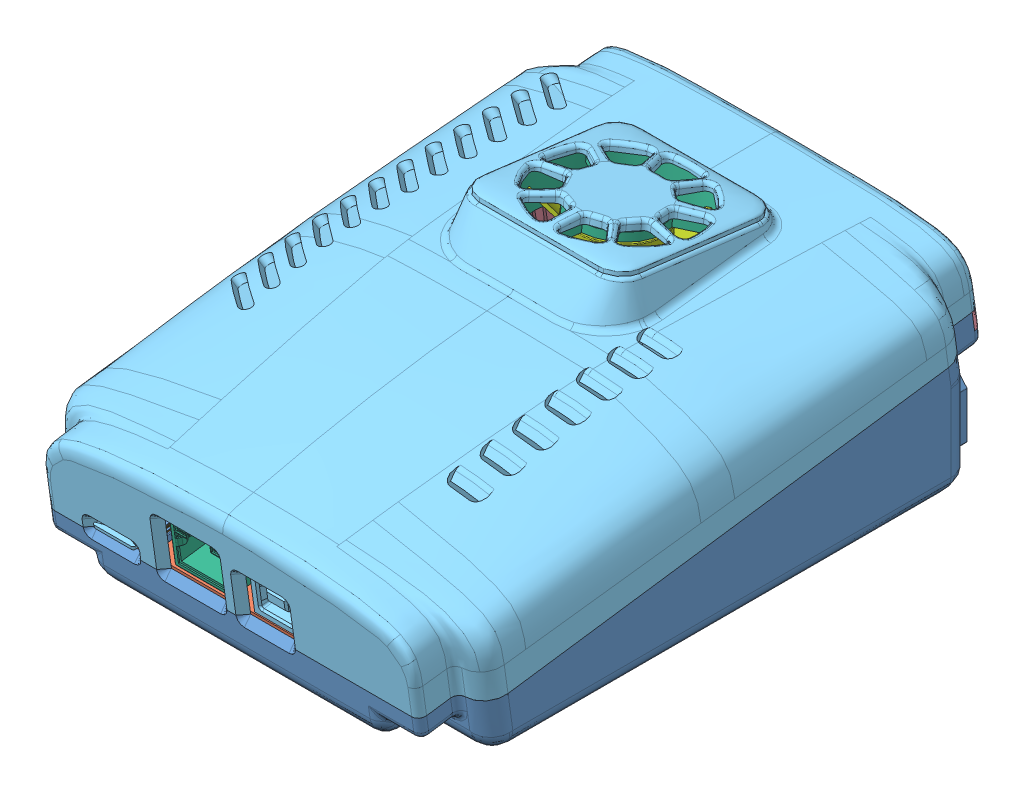
SolidWorks assembly MKS Sbase case new, configuration Default. Lengths in mm.
Overall size (115.99 69.47 159.81).
163 component instances, 61 part files, 40 mates.
Components (placement in the parent):
- MKS SBase case bottom V1.3-1: MKS SBase case bottom V1.3 [Default] at origin size (115.99 31.84 151.44)
- MKS SBase V1.3-1: MKS SBase V1.3 [Default] at (0 1.2873 0.1809) x (0 0.139173 -0.990268) z (1 0 0) size (148.75 28.07 98.65)
  - MKS SBase PCB-1: MKS SBase PCB [Default] at origin size (146.5 1.6 95)
  - 10 pin male socket -2: 10 pin male socket  [Default] at (92.5901 0 -6.7406) x (0 0 -1) z (1 0 0) size (20.25 12.5 9)
  - 10 pin male socket -3: 10 pin male socket  [Default] at (92.5901 0 -28.4906) x (0 0 -1) z (1 0 0) size (20.25 12.5 9)
  - 6 pin terminal block-1: 6 pin terminal block [Default] at (-13.25 0 37.7021) size (30.6 13.8 8.3)
  - USB socket-1: USB socket [Default] at (-15.2875 4.6912 16.0684) size (16.5 14.22 14.86)
  - JST XH 4 Purple-1: JST XH 4 Purple [Default] at (56.25 0 -43.725) x (-1 0 0) z (0 0 -1) size (12.4 10.45 5.75)
  - JST XH 4 Black-1: JST XH 4 Black [Default] at (36.35 0 -43.725) x (-1 0 0) z (0 0 -1) size (12.4 10.45 5.75)
  - JST XH 4 Blue-1: JST XH 4 Blue [Default] at (-3.45 0 -43.725) x (-1 0 0) z (0 0 -1) size (12.4 10.45 5.75)
  - JST XH 4 Green-1: JST XH 4 Green [Default] at (16.45 0 -43.725) x (-1 0 0) z (0 0 -1) size (12.4 10.45 5.75)
  - JST XH 4 Red-1: JST XH 4 Red [Default] at (-23.35 0 -43.725) x (-1 0 0) z (0 0 -1) size (12.4 10.45 5.75)
  - JST XH 2 Black-1: JST XH 2 Black [Default] at (13.85 0 44.225) size (7.4 10.45 5.75)
  - JST XH 2 Purple-1: JST XH 2 Purple [Default] at (21.75 0 44.225) size (7.4 10.45 5.75)
  - JST XH 2 White-1: JST XH 2 White [Default] at (5.95 0 44.225) size (7.4 10.45 5.75)
  - JST XH 3 Blue-1: JST XH 3 Blue [Default] at (55.4 0 14.725) x (-1 0 0) z (0 0 -1) size (9.9 10.45 5.75)
  - JST XH 3 Green-1: JST XH 3 Green [Default] at (55.4 0 31.025) x (-1 0 0) z (0 0 -1) size (9.9 10.45 5.75)
  - JST XH 3 Red-1: JST XH 3 Red [Default] at (55.4 0 -1.575) x (-1 0 0) z (0 0 -1) size (9.9 10.45 5.75)
  - JST XH 2 White-2: JST XH 2 White [Default] at (29.65 0 44.225) size (7.4 10.45 5.75)
  - 8 pin male socket -1: 8 pin male socket  [Default] at (71.2406 0 66.9901) size (17.85 12.5 9)
  - JST XH 3 Blue-2: JST XH 3 Blue [Default] at (55.4 0 6.675) x (-1 0 0) z (0 0 -1) size (9.9 10.45 5.75)
  - JST XH 3 Green-2: JST XH 3 Green [Default] at (55.4 0 22.975) x (-1 0 0) z (0 0 -1) size (9.9 10.45 5.75)
  - JST XH 3 Red-2: JST XH 3 Red [Default] at (55.4 0 -9.625) x (-1 0 0) z (0 0 -1) size (9.9 10.45 5.75)
  - microSD_Connector-1: microSD_Connector [Default] at (-65.65 0 -31.475) x (0 0 -1) z (1 0 0) size (14.1 2.14 15.45)
    - microSD_Body-1: microSD_Body [Default] at origin size (14.1 1.85 15.2)
    - microSD_Cover-1: microSD_Cover [Default] at (0 1.7 0) x (1 0 0) z (0 0 -1) size (13.95 1.9 15.2)
    - microSD_Card_Detect-1: microSD_Card_Detect [Default] at (4.99 -0.05 7.4) size (4.45 1.9 2.05)
    - microSD_Spring-2: microSD_Spring [Default] at (-3.85 1.125 6.9) x (-0.521999 -0.852946 0) z (0.852946 -0.521999 0) size (1.41 10.35 1.43)
    - microSD_Pin-1: microSD_Pin [11.15] at (5.725 -0.05 -2) x (0 0 1) z (-1 0 0) size (7.35 1.15 0.6)
    - microSD_Pin-2: microSD_Pin [11.15] at (4.625 -0.05 -2) x (0 0 1) z (-1 0 0) size (7.35 1.15 0.6)
    - microSD_Pin-3: microSD_Pin [11.35] at (3.525 -0.05 -2) x (0 0 1) z (-1 0 0) size (7.35 1.15 0.6)
    - microSD_Pin-4: microSD_Pin [11.15] at (2.425 -0.05 -2) x (0 0 1) z (-1 0 0) size (7.35 1.15 0.6)
    - microSD_Pin-5: microSD_Pin [11.35] at (1.325 -0.05 -2) x (0 0 1) z (-1 0 0) size (7.35 1.15 0.6)
    - microSD_Pin-6: microSD_Pin [11.15] at (0.225 -0.05 -2) x (0 0 1) z (-1 0 0) size (7.35 1.15 0.6)
    - microSD_Pin-7: microSD_Pin [10.75] at (-0.875 -0.05 -2) x (0 0 1) z (-1 0 0) size (7.25 1.15 0.6)
    - microSD_Pin-8: microSD_Pin [11.15] at (-1.975 -0.05 -2) x (0 0 1) z (-1 0 0) size (7.35 1.15 0.6)
  - Micro SD Card-1: Micro SD Card [Default] at (-68 1.05 -33.35) x (0 0 1) z (-1 0 0) size (11 0.83 15)
  - RJ45_10P_TJ3009-1: RJ45_10P_TJ3009 [Default] at (-61.925 0.35 -11.1) x (0 0 1) z (-1 0 0) size (16 15.87 21.5)
  - Condensator-1: Condensator [Default] at (-65.75 0.15 24) x (-1 0 0) z (0 0 -1) size (13.15 23 13.15)
  - Condensator-2: Condensator [Default] at (-50.75 0.15 24) x (-1 0 0) z (0 0 -1) size (13.15 23 13.15)
  - 2.54 pins 4 x 1-1: 2.54 pins 4 x 1 [Default] at (-14.68 0 -18.75) x (1 0 0) z (0 0 -1) size (10.06 11 2.5)
  - 2.54 pins 4 x 1-5: 2.54 pins 4 x 1 [Default] at (25.12 0 -18.75) x (1 0 0) z (0 0 -1) size (10.06 11 2.5)
  - 2.54 pins 4 x 1-6: 2.54 pins 4 x 1 [Default] at (45.02 0 -18.75) x (1 0 0) z (0 0 -1) size (10.06 11 2.5)
  - 2.54 pins 4 x 1-7: 2.54 pins 4 x 1 [Default] at (64.92 0 -18.75) x (1 0 0) z (0 0 -1) size (10.06 11 2.5)
  - 2.54 pins 4 x 1-8: 2.54 pins 4 x 1 [Default] at (5.22 0 -18.75) x (1 0 0) z (0 0 -1) size (10.06 11 2.5)
  - 2.54 pins 6 x 1-1: 2.54 pins 6 x 1 [Default] at (71 0 -37.8175) x (0 0 1) z (-1 0 0) size (15.09 11 2.5)
  - 2.54 pins 6 x 1-3: 2.54 pins 6 x 1 [Default] at (-51.2675 0 -45.4) size (15.09 11 2.5)
  - 2.54 pins 3 x 1-3: 2.54 pins 3 x 1 [Default] at (55.6125 0 36.35) size (7.47 11 2.5)
  - 2.54 pins 3 x 1-4: 2.54 pins 3 x 1 [Default] at (64.6 0 -30.2125) x (0 0 -1) z (1 0 0) size (7.47 11 2.5)
  - 2.54 pins 2 x 1-1: 2.54 pins 2 x 1 [Default] at (4.5 0 19.2475) x (0 0 -1) z (1 0 0) size (4.93 11 2.5)
  - 2.54 pins 3 x 2-3: 2.54 pins 3 x 2 [Default] at (-42.5 0.64 7.0875) x (0 0 -1) z (1 0 0) size (7.47 8.64 7.5)
  - Stepper driver heatsink-1: Stepper driver heatsink [Default] at (15.75 9.25 -28.85) x (0 0 -1) z (1 0 0) size (6 13.5 90)
  - Stepper driver-1: Stepper driver [Default] at (55.75 1.35 -28.85) x (0 0 -1) z (1 0 0) size (8 2.5 10.5)
  - Stepper driver-2: Stepper driver [Default] at (35.75 1.35 -28.85) x (0 0 -1) z (1 0 0) size (8 2.5 10.5)
  - Stepper driver-3: Stepper driver [Default] at (15.75 1.35 -28.85) x (0 0 -1) z (1 0 0) size (8 2.5 10.5)
  - Stepper driver-4: Stepper driver [Default] at (-4.25 1.35 -28.85) x (0 0 -1) z (1 0 0) size (8 2.5 10.5)
  - Stepper driver-5: Stepper driver [Default] at (-24.25 1.35 -28.85) x (0 0 -1) z (1 0 0) size (8 2.5 10.5)
  - Power terminal block-1: Power terminal block [Default] at (-51.75 0 42.25) x (-1 0 0) z (0 0 -1) size (10.55 20.8 10.5)
  - Power terminal block-2: Power terminal block [Default] at (-34.75 0 42.25) x (-1 0 0) z (0 0 -1) size (10.55 20.8 10.5)
  - Elco100_35-5: Elco100_35 [Default] at (-30.25 0.64 -4.7) x (0 0 1) z (-1 0 0) size (6.6 6.95 7)
  - Elco100_35-6: Elco100_35 [Default] at (24.65 0.64 11.3) x (0 0 -1) z (1 0 0) size (6.6 6.95 7)
  - Elco100_35-7: Elco100_35 [Default] at (-32.05 0.64 -36) x (0 0 -1) z (1 0 0) size (6.6 6.95 7)
  - Elco100_35-8: Elco100_35 [Default] at (-12.05 0.64 -36) x (0 0 -1) z (1 0 0) size (6.6 6.95 7)
  - Elco100_35-9: Elco100_35 [Default] at (7.95 0.64 -36) x (0 0 -1) z (1 0 0) size (6.6 6.95 7)
  - Elco100_35-10: Elco100_35 [Default] at (27.95 0.64 -36) x (0 0 -1) z (1 0 0) size (6.6 6.95 7)
  - Elco100_35-11: Elco100_35 [Default] at (47.95 0.64 -36) x (0 0 -1) z (1 0 0) size (6.6 6.95 7)
  - Elco10_35-1: Elco10_35 [Default] at (35.2 0.64 35.25) size (4.3 4.65 4.6)
  - Elco10_35-2: Elco10_35 [Default] at (28.35 0.64 35.25) size (4.3 4.65 4.6)
  - Elco10_35-3: Elco10_35 [Default] at (21.5 0.64 35.25) size (4.3 4.65 4.6)
  - Elco10_35-4: Elco10_35 [Default] at (14.65 0.64 35.25) size (4.3 4.65 4.6)
  - Power FAT heatsink-1: Power FAT heatsink [Default] at (-16.55 2 30.7) size (55 11.25 8.49)
  - Power FAT-1: Power FAT [Default] at (-34.925 0 30.7) x (-1 0 0) z (0 0 -1) size (6.35 2 11)
  - Power FAT-2: Power FAT [Default] at (-22.675 0 30.7) x (-1 0 0) z (0 0 -1) size (6.35 2 11)
  - Power FAT-3: Power FAT [Default] at (-10.425 0 30.7) x (-1 0 0) z (0 0 -1) size (6.35 2 11)
  - Power FAT-4: Power FAT [Default] at (1.825 0 30.7) x (-1 0 0) z (0 0 -1) size (6.35 2 11)
  - Series of LEDs-1: Series of LEDs [Default] at (-46.425 0 -41.575) size (10.85 0.6 1.75)
  - Reset button-1: Reset button [Default] at (59.9 0 43.2) size (9.25 2.95 6.02)
  - 4 LEDs power outputs-1: 4 LEDs power outputs [Default] at (-12.2 0 25.075) size (37.6 0.6 1.75)
  - LPC1768 ARM Cortex M3-1: LPC1768 ARM Cortex M3 [Default] at (-15.75 0 2.3) size (17 1.4 17)
  - Elco10_35-6: Elco10_35 [Default] at (-29.9 0.64 -10.6) x (0 0 1) z (-1 0 0) size (4.3 4.65 4.6)
  - Elco10_35-7: Elco10_35 [Default] at (2.4 0.64 -9.1) size (4.3 4.65 4.6)
  - Elco10_35-8: Elco10_35 [Default] at (15.6 0.64 3.35) size (4.3 4.65 4.6)
  - Elco10_35-9: Elco10_35 [Default] at (-37.9 0.64 -20.4) size (4.3 4.65 4.6)
  - JST Stepper connector assembly-1: JST Stepper connector assembly [Default] at (36.35 1.2 -43.75) size (12.3 15.75 8.2)
    - JST XHP 4-1: JST XHP 4 [Default] at origin size (12.3 8 5.45)
    - JSH XHP Contact Pin-1: JSH XHP Contact Pin [Default] at (-3.75 1 0.25) size (2 6.61 2.5)
    - JSH XHP Contact Pin-2: JSH XHP Contact Pin [Default] at (3.75 1 0.25) size (2 6.61 2.5)
    - JSH XHP Contact Pin-3: JSH XHP Contact Pin [Default] at (1.25 1 0.25) size (2 6.61 2.5)
    - JSH XHP Contact Pin-4: JSH XHP Contact Pin [Default] at (-1.25 1 0.25) size (2 6.61 2.5)
    - Stepper wire Black-1: Stepper wire Black [Default] at (3.75 0 -0.0046) size (1.4 15.75 6.79)
    - Stepper wire Green-1: Stepper wire Green [Default] at (1.25 0 -0.0046) size (1.4 15.75 6.79)
    - Stepper wire Red-1: Stepper wire Red [Default] at (-1.25 0 -0.0046) size (1.4 15.75 6.79)
    - Stepper wire Blue-1: Stepper wire Blue [Default] at (-3.75 0 -0.0046) size (1.4 15.75 6.79)
  - JST Stepper connector assembly-2: JST Stepper connector assembly [Default] at (16.45 1.2 -43.75) size (12.3 15.75 8.2)
    - JST XHP 4-1: JST XHP 4 [Default] at origin size (12.3 8 5.45)
    - JSH XHP Contact Pin-1: JSH XHP Contact Pin [Default] at (-3.75 1 0.25) size (2 6.61 2.5)
    - JSH XHP Contact Pin-2: JSH XHP Contact Pin [Default] at (3.75 1 0.25) size (2 6.61 2.5)
    - JSH XHP Contact Pin-3: JSH XHP Contact Pin [Default] at (1.25 1 0.25) size (2 6.61 2.5)
    - JSH XHP Contact Pin-4: JSH XHP Contact Pin [Default] at (-1.25 1 0.25) size (2 6.61 2.5)
    - Stepper wire Black-1: Stepper wire Black [Default] at (3.75 0 -0.0046) size (1.4 15.75 6.79)
    - Stepper wire Green-1: Stepper wire Green [Default] at (1.25 0 -0.0046) size (1.4 15.75 6.79)
    - Stepper wire Red-1: Stepper wire Red [Default] at (-1.25 0 -0.0046) size (1.4 15.75 6.79)
    - Stepper wire Blue-1: Stepper wire Blue [Default] at (-3.75 0 -0.0046) size (1.4 15.75 6.79)
  - JST Stepper connector assembly-3: JST Stepper connector assembly [Default] at (-3.45 1.2 -43.75) size (12.3 15.75 8.2)
    - JST XHP 4-1: JST XHP 4 [Default] at origin size (12.3 8 5.45)
    - JSH XHP Contact Pin-1: JSH XHP Contact Pin [Default] at (-3.75 1 0.25) size (2 6.61 2.5)
    - JSH XHP Contact Pin-2: JSH XHP Contact Pin [Default] at (3.75 1 0.25) size (2 6.61 2.5)
    - JSH XHP Contact Pin-3: JSH XHP Contact Pin [Default] at (1.25 1 0.25) size (2 6.61 2.5)
    - JSH XHP Contact Pin-4: JSH XHP Contact Pin [Default] at (-1.25 1 0.25) size (2 6.61 2.5)
    - Stepper wire Black-1: Stepper wire Black [Default] at (3.75 0 -0.0046) size (1.4 15.75 6.79)
    - Stepper wire Green-1: Stepper wire Green [Default] at (1.25 0 -0.0046) size (1.4 15.75 6.79)
    - Stepper wire Red-1: Stepper wire Red [Default] at (-1.25 0 -0.0046) size (1.4 15.75 6.79)
    - Stepper wire Blue-1: Stepper wire Blue [Default] at (-3.75 0 -0.0046) size (1.4 15.75 6.79)
  - JST Stepper connector assembly-4: JST Stepper connector assembly [Default] at (-23.35 1.2 -43.75) size (12.3 15.75 8.2)
    - JST XHP 4-1: JST XHP 4 [Default] at origin size (12.3 8 5.45)
    - JSH XHP Contact Pin-1: JSH XHP Contact Pin [Default] at (-3.75 1 0.25) size (2 6.61 2.5)
    - JSH XHP Contact Pin-2: JSH XHP Contact Pin [Default] at (3.75 1 0.25) size (2 6.61 2.5)
    - JSH XHP Contact Pin-3: JSH XHP Contact Pin [Default] at (1.25 1 0.25) size (2 6.61 2.5)
    - JSH XHP Contact Pin-4: JSH XHP Contact Pin [Default] at (-1.25 1 0.25) size (2 6.61 2.5)
    - Stepper wire Black-1: Stepper wire Black [Default] at (3.75 0 -0.0046) size (1.4 15.75 6.79)
    - Stepper wire Green-1: Stepper wire Green [Default] at (1.25 0 -0.0046) size (1.4 15.75 6.79)
    - Stepper wire Red-1: Stepper wire Red [Default] at (-1.25 0 -0.0046) size (1.4 15.75 6.79)
    - Stepper wire Blue-1: Stepper wire Blue [Default] at (-3.75 0 -0.0046) size (1.4 15.75 6.79)
  - L7812C2T Power regulator-1: L7812C2T Power regulator [Default] at (19 0 22.1) x (0 0 1) z (-1 0 0) size (10 4.5 15)
  - Elco22_35-1: Elco22_35 [Default] at (42.9 0.64 5) size (5.3 6.15 5.5)
  - Inductance 101-1: Inductance 101 [Default] at (41.25 0 21) size (10 5 13)
  - JST Endstop connector assembly-5: JST Endstop connector assembly [Default] at (55.4 1.2 14.7) size (9.8 8 5.45)
    - JST XHP 3-1: JST XHP 3 [Default] at origin size (9.8 8 5.45)
    - JSH XHP Contact Pin-1: JSH XHP Contact Pin [Default] at (-2.5 1 0.25) size (2 6.61 2.5)
    - JSH XHP Contact Pin-2: JSH XHP Contact Pin [Default] at (0 1 0.25) size (2 6.61 2.5)
    - JSH XHP Contact Pin-3: JSH XHP Contact Pin [Default] at (2.5 1 0.25) size (2 6.61 2.5)
  - JST Endstop connector assembly-3: JST Endstop connector assembly [Default] at (55.4 1.2 22.95) size (9.8 8 5.45)
    - JST XHP 3-1: JST XHP 3 [Default] at origin size (9.8 8 5.45)
    - JSH XHP Contact Pin-1: JSH XHP Contact Pin [Default] at (-2.5 1 0.25) size (2 6.61 2.5)
    - JSH XHP Contact Pin-2: JSH XHP Contact Pin [Default] at (0 1 0.25) size (2 6.61 2.5)
    - JSH XHP Contact Pin-3: JSH XHP Contact Pin [Default] at (2.5 1 0.25) size (2 6.61 2.5)
  - Xstop wire assembly-1: Xstop wire assembly [Default] at (55.4 1.2 -1.6) size (9.8 20.77 53.74)
    - JST Endstop connector assembly-1: JST Endstop connector assembly [Default] at origin size (9.8 8 5.45)
      - JST XHP 3-1: JST XHP 3 [Default] at origin size (9.8 8 5.45)
      - JSH XHP Contact Pin-1: JSH XHP Contact Pin [Default] at (-2.5 1 0.25) size (2 6.61 2.5)
      - JSH XHP Contact Pin-2: JSH XHP Contact Pin [Default] at (0 1 0.25) size (2 6.61 2.5)
      - JSH XHP Contact Pin-3: JSH XHP Contact Pin [Default] at (2.5 1 0.25) size (2 6.61 2.5)
    - XStop wire Black-1: XStop wire Black [Default] at (0 5.7 0.6354) size (1.4 20.77 51.11)
    - XStop wire Red-1: XStop wire Red [Default] at (2.5 5.7 0.6354) size (1.4 20.77 51.11)
    - XStop wire white-1: XStop wire white [Default] at (-2.5 5.7 0.6354) size (1.4 20.77 51.11)
- XT60 Stecker-1: XT60 Stecker [Default] at (47.9 -8.1533 -53.4143) x (0 -1 0) z (0 0 -1) size (15.6 8 21.4)
- Flatwire connectors-1: Flatwire connectors [Default] at (0 -4.9033 -79.2362) size (64.01 20.2 19.5)
  - 10 pin socket transfer port mainboard V2-1: 10 pin socket transfer port mainboard V2 [Default] at (-26.7 0 0) x (0 -1 0) z (-1 0 0) size (20.2 19.5 10.61)
  - 10 pin socket transfer port mainboard V2-2: 10 pin socket transfer port mainboard V2 [Default] at (-17.8 0 0) x (0 -1 0) z (-1 0 0) size (20.2 19.5 10.61)
  - 10 pin socket transfer port mainboard V2-3: 10 pin socket transfer port mainboard V2 [Default] at (-8.9 0 0) x (0 -1 0) z (-1 0 0) size (20.2 19.5 10.61)
  - 10 pin socket transfer port mainboard V2-4: 10 pin socket transfer port mainboard V2 [Default] x (0 -1 0) z (-1 0 0) size (20.2 19.5 10.61)
  - 10 pin socket transfer port mainboard V2-5: 10 pin socket transfer port mainboard V2 [Default] at (8.9 0 0) x (0 -1 0) z (-1 0 0) size (20.2 19.5 10.61)
  - 10 pin socket transfer port mainboard V2-6: 10 pin socket transfer port mainboard V2 [Default] at (17.8 0 0) x (0 -1 0) z (-1 0 0) size (20.2 19.5 10.61)
  - 10 pin socket transfer port mainboard V2-7: 10 pin socket transfer port mainboard V2 [Default] at (26.7 0 0) x (0 -1 0) z (-1 0 0) size (20.2 19.5 10.61)
- Rubber pad-1: Rubber pad [Default] at (45 -21.1533 -51.5) size (9.9 2.5 9.9)
- Rubber pad-2: Rubber pad [Default] at (-45 -21.1533 -51.5) size (9.9 2.5 9.9)
- Rubber pad-3: Rubber pad [Default] at (45 -21.1533 51.5) size (9.9 2.5 9.9)
- Rubber pad-4: Rubber pad [Default] at (-45 -21.1533 51.5) size (9.9 2.5 9.9)
- Flatwire connector support V1.1-1: Flatwire connector support V1.1 [Default] at (0 6.2516 -68.1936) x (1 0 0) z (0 -0.139173 0.990268) size (100 9.25 18.69)
- MKS case top 2.0-1: MKS case top 2.0 [Default] at (0 1.4854 0.2088) x (1 0 0) z (0 -0.139173 0.990268) size (115.52 36.61 152.02)
- 40 x 40 x 10 Fan assembly-1: 40 x 40 x 10 Fan assembly [Default] at (0 29.7654 -27.5126) x (0 -0.121869 -0.992546) z (0 0.992546 -0.121869) size (43.51 43.41 10.23)
  - 40 x 40 x 10 Fan Case-1: 40 x 40 x 10 Fan Case [Default] x (-1 0 0) z (0 0 -1) size (40 40 10)
  - 40 x 40 x 10 Fan Rotor-1: 40 x 40 x 10 Fan Rotor [Default] at (0 0 -4.7) x (0.992079 0.125613 0) z (0.125613 -0.992079 0) size (38.94 9.45 38.83)
Mates (geometry in assembly coordinates):
- Coincident24: coincident aligned: plane of MKS SBase case bottom V1.3-1 through (0 0 0) normal (0 0 1); plane of assembly through (0 0 0) normal (0 0 1)
- Coincident25: coincident aligned: plane of MKS SBase case bottom V1.3-1 through (0 0 0) normal (0 1 0); plane of assembly through (0 0 0) normal (0 1 0)
- Coincident26: coincident aligned: plane of MKS SBase case bottom V1.3-1 through (0 0 0) normal (1 0 0); plane of assembly through (0 0 0) normal (1 0 0)
- Coincident27: coincident anti-aligned: plane of MKS SBase case bottom V1.3-1 through (0 -0.2971 -0.0418) normal (0 0.990268 0.139173); plane of MKS SBase V1.3-1/MKS SBase PCB-1 through (0 -0.2971 -0.0418) normal (0 -0.990268 -0.139173)
- Parallel1: parallel aligned: plane of MKS SBase case bottom V1.3-1 through (50 0 -65.4143) normal (0 0 -1); plane of XT60 Stecker-1 through (47.9 -8.1533 -69.8143) normal (0 0 -1)
- Parallel2: parallel aligned: plane of MKS SBase case bottom V1.3-1 through (57.75 -20.0533 -75.9143) normal (0 -1 0); plane of XT60 Stecker-1 through (51.9 -15.9533 -53.4143) normal (0 -1 0)
- Distance3: distance = 0.1 mm anti-aligned: plane of MKS SBase case bottom V1.3-1 through (51.7 -16.0533 -53.4143) normal (0 1 0); plane of XT60 Stecker-1 through (51.9 -15.9533 -53.4143) normal (0 -1 0)
- Distance4: distance = 0.1 mm anti-aligned: plane of MKS SBase case bottom V1.3-1 through (52 -15.7533 -53.4143) normal (-1 0 0); plane of XT60 Stecker-1 through (51.9 -3.3533 -53.4143) normal (1 0 0)
- Coincident37: coincident anti-aligned: plane of MKS SBase case bottom V1.3-1 through (51.7 -15.7533 -53.4143) normal (0 0 -1); plane of XT60 Stecker-1 through (47.9 -8.1533 -53.4143) normal (0 0 1)
- Coincident55: coincident aligned: plane of Rubber pad-1 through (45 -21.1533 -51.5) normal (0 -1 0); plane of Rubber pad-2 through (-45 -21.1533 -51.5) normal (0 -1 0)
- Coincident56: coincident aligned: plane of Rubber pad-2 through (-45 -21.1533 -51.5) normal (0 -1 0); plane of Rubber pad-3 through (45 -21.1533 51.5) normal (0 -1 0)
- Coincident57: coincident aligned: plane of Rubber pad-3 through (45 -21.1533 51.5) normal (0 -1 0); plane of Rubber pad-4 through (-45 -21.1533 51.5) normal (0 -1 0)
- Coincident58: coincident anti-aligned: plane of MKS SBase case bottom V1.3-1 through (45 -18.6533 -51.5) normal (0 -1 0); plane of Rubber pad-1 through (45 -18.6533 -51.5) normal (0 1 0)
- Concentric3: concentric aligned: cylinder of MKS SBase case bottom V1.3-1 through (45 -18.6533 -51.5) axis (0 -1 0) radius 5.05; cylinder of Rubber pad-1 through (45 -18.6533 -51.5) axis (0 -1 0) radius 4.95
- Concentric4: concentric aligned: cylinder of MKS SBase case bottom V1.3-1 through (45 -18.6533 51.5) axis (0 -1 0) radius 5.05; cylinder of Rubber pad-3 through (45 -18.6533 51.5) axis (0 -1 0) radius 4.95
- Concentric5: concentric aligned: cylinder of MKS SBase case bottom V1.3-1 through (-45 -18.6533 51.5) axis (0 -1 0) radius 5.05; cylinder of Rubber pad-4 through (-45 -18.6533 51.5) axis (0 -1 0) radius 4.95
- Concentric6: concentric aligned: cylinder of MKS SBase case bottom V1.3-1 through (-45 -18.6533 -51.5) axis (0 -1 0) radius 5.05; cylinder of Rubber pad-2 through (-45 -18.6533 -51.5) axis (0 -1 0) radius 4.95
- Concentric7: concentric aligned: cylinder of MKS SBase case bottom V1.3-1 through (43.75 -20.4629 -73.0589) axis (0 0.990268 0.139173) radius 1; cylinder of Flatwire connector support V1.1-1 through (43.75 1.9221 -69.9129) axis (0 0.990268 0.139173) radius 1
- Concentric8: concentric aligned: cylinder of MKS SBase case bottom V1.3-1 through (-43.75 -20.4629 -73.0589) axis (0 0.990268 0.139173) radius 1; cylinder of Flatwire connector support V1.1-1 through (-43.75 1.9221 -69.9129) axis (0 0.990268 0.139173) radius 1
- Concentric9: concentric anti-aligned: cylinder of MKS SBase case bottom V1.3-1 through (-43.75 -20.4629 -73.0589) axis (0 0.990268 0.139173) radius 1; circle of MKS SBase V1.3-1/MKS SBase PCB-1
- Concentric10: concentric anti-aligned: cylinder of MKS SBase case bottom V1.3-1 through (43.75 -39.808 64.5884) axis (0 0.990268 0.139173) radius 1; circle of MKS SBase V1.3-1/MKS SBase PCB-1
- Symmetric1: symmetric aligned: plane of MKS SBase case bottom V1.3-1 through (0 0 0) normal (1 0 0); plane of Flatwire connectors-1/10 pin socket transfer port mainboard V2-1 through (-31.15 5.1967 -72.7362) normal (-1 0 0); plane of Flatwire connectors-1/10 pin socket transfer port mainboard V2-7 through (31.15 5.1967 -72.7362) normal (1 0 0)
- Parallel4: parallel anti-aligned: plane of MKS SBase case bottom V1.3-1 through (-30.45 -15.0533 -72.9143) normal (0 1 0); plane of Flatwire connectors-1/10 pin socket transfer port mainboard V2-6 through (22.25 -15.0033 -72.7362) normal (0 -1 0)
- Coincident66: coincident: plane of MKS SBase case bottom V1.3-1 through (0 -11.0533 -59.6691) normal (0 0.052336 -0.99863); line of Flatwire connectors-1/10 pin socket transfer port mainboard V2-5 through (11.7743 -12.3333 -59.7362) axis (1 0 0)
- Coincident67: coincident anti-aligned: plane of MKS SBase case bottom V1.3-1 through (0 -3.2679 -0.4593) normal (0 0.990268 0.139173); plane of Flatwire connector support V1.1-1 through (47.6 6.2516 -68.1936) normal (0 -0.990268 -0.139173)
- Coincident68: coincident aligned: plane of MKS SBase case bottom V1.3-1 through (0 0 0) normal (1 0 0); plane of MKS case top 2.0-1
- Coincident69: coincident anti-aligned: plane of MKS SBase case bottom V1.3-1 through (57.75 -9.0918 75.4691) normal (0 0.990268 0.139173); plane of MKS case top 2.0-1 through (48 1.4854 0.2088) normal (0 -0.990268 -0.139173)
- Coincident70: coincident aligned: plane of Flatwire connector support V1.1-1 through (50 7.3093 -75.7196) normal (0 0.139173 -0.990268); plane of MKS case top 2.0-1 through (48 12.0626 -75.0516) normal (0 0.139173 -0.990268)
- Coincident71: coincident aligned: plane of MKS SBase case bottom V1.3-1 through (0 0 0) normal (1 0 0); plane of MKS case top 2.0-1
- Coincident72: coincident aligned: plane of MKS SBase case bottom V1.3-1 through (57.75 -9.0918 75.4691) normal (0 0.990268 0.139173); plane of MKS case top 2.0-1 through (0 1.4854 0.2088) normal (0 0.990268 0.139173)
- Concentric11: concentric aligned: circle of Flatwire connector support V1.1-1; circle of MKS case top 2.0-1
- Coincident73: coincident anti-aligned: plane of MKS case top 2.0-1 through (48 16.0078 60.8169) normal (0 -0.549746 -0.835332); plane of ? through (0 30.1015 51.5416) normal (0 0.549746 0.835332)
- Coincident75: coincident anti-aligned: plane of MKS case top 2.0-1; plane of ?
- Concentric12: concentric anti-aligned: cylinder of MKS SBase case bottom V1.3-1 through (43.75 -39.808 64.5884) axis (0 0.990268 0.139173) radius 1; cylinder of MKS case top 2.0-1 through (43.75 -4.2261 69.5891) axis (0 -0.990268 -0.139173) radius 1.6
- Concentric13: concentric anti-aligned: cylinder of MKS SBase case bottom V1.3-1 through (-43.75 -20.4629 -73.0589) axis (0 0.990268 0.139173) radius 1; cylinder of MKS case top 2.0-1 through (-43.75 15.119 -68.0582) axis (0 -0.990268 -0.139173) radius 1.6
- Coincident76: coincident anti-aligned: plane of MKS SBase case bottom V1.3-1 through (57.75 -9.0918 75.4691) normal (0 0.990268 0.139173); plane of MKS case top 2.0-1 through (0 1.4854 0.2088) normal (0 -0.990268 -0.139173)
- Coincident77: coincident anti-aligned: plane of MKS SBase case bottom V1.3-1 through (0 0 0) normal (1 0 0); plane of 40 x 40 x 10 Fan assembly-1
- Angle1: planar angle = 0.261799 rad aligned: plane of MKS case top 2.0-1 through (0 1.4854 0.2088) normal (0 0.990268 0.139173); plane of 40 x 40 x 10 Fan assembly-1/40 x 40 x 10 Fan Case-1 through (0 34.7282 -28.1219) normal (0 0.992546 -0.121869)
- Distance6: distance = 52 mm: plane of MKS case top 2.0-1 through (0 1.4854 0.2088) normal (0 -0.139173 0.990268); line of 40 x 40 x 10 Fan assembly-1/40 x 40 x 10 Fan Case-1 through (-16 32.2908 -47.9729) axis (1 0 0)
- Distance7: distance = 24 mm: line of 40 x 40 x 10 Fan assembly-1/40 x 40 x 10 Fan Case-1 through (-16 32.2908 -47.9729) axis (1 0 0); plane of MKS SBase V1.3-1/MKS SBase PCB-1 through (0 1.2873 0.1809) normal (0 0.990268 0.139173)
